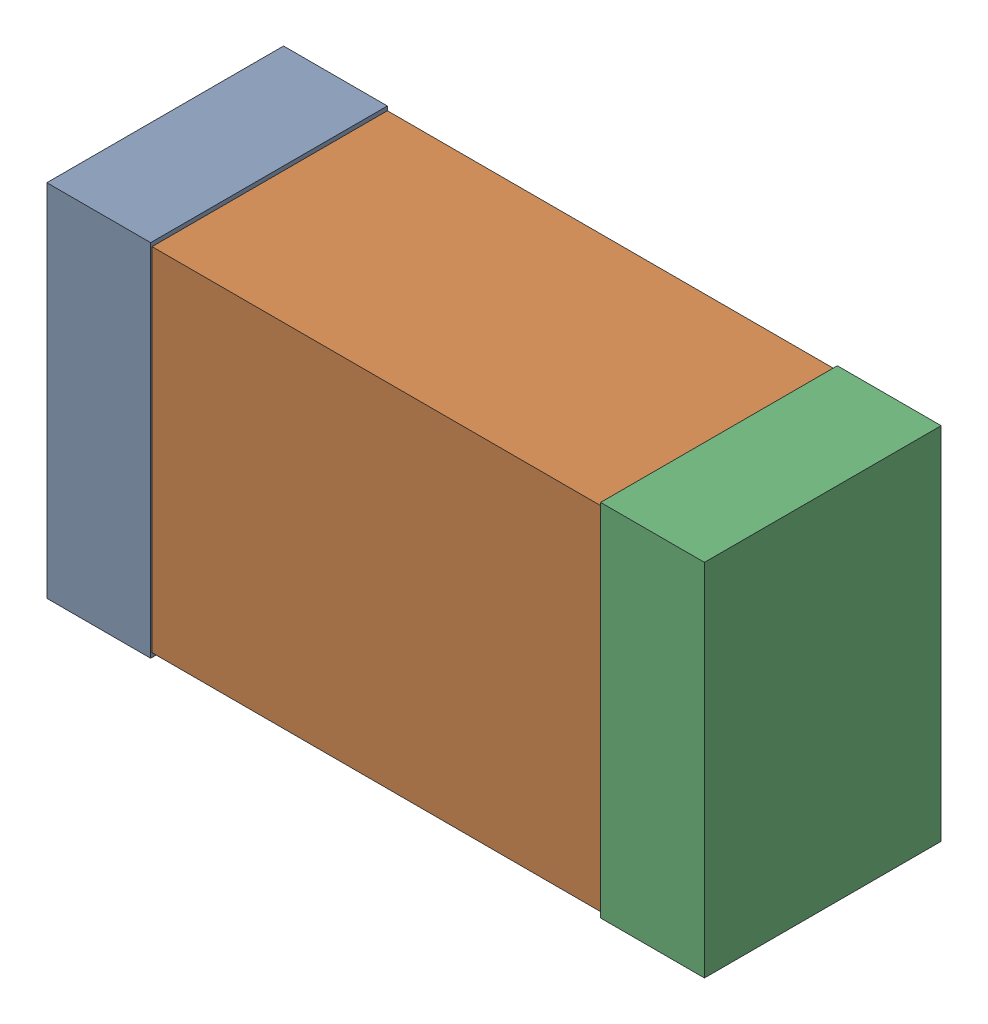
SolidWorks assembly C7Kanaloa_v2.0.0_GPIO_b, configuration Default. Lengths in mm.
Overall size (2.38 1.3 0.85).
6 component instances, 2 part files, 0 mates.
Components (placement in the parent):
- 352877648-1: 352877648 [Default] at (83.328 43.942 0) size (0.38 1.3 0.85)
  - Extruded_14-1: Extruded_14 [Default] at origin size (0.38 1.3 0.85)
- 352877904-1: 352877904 [Default] at (84.328 43.942 0) size (2.2 1.27 0.85)
  - Extruded_18-1: Extruded_18 [Default] at origin size (2.2 1.27 0.85)
- 352877648-2: 352877648 [Default] at (85.328 43.942 0) size (0.38 1.3 0.85)
  - Extruded_14-1: Extruded_14 [Default] at origin size (0.38 1.3 0.85)
